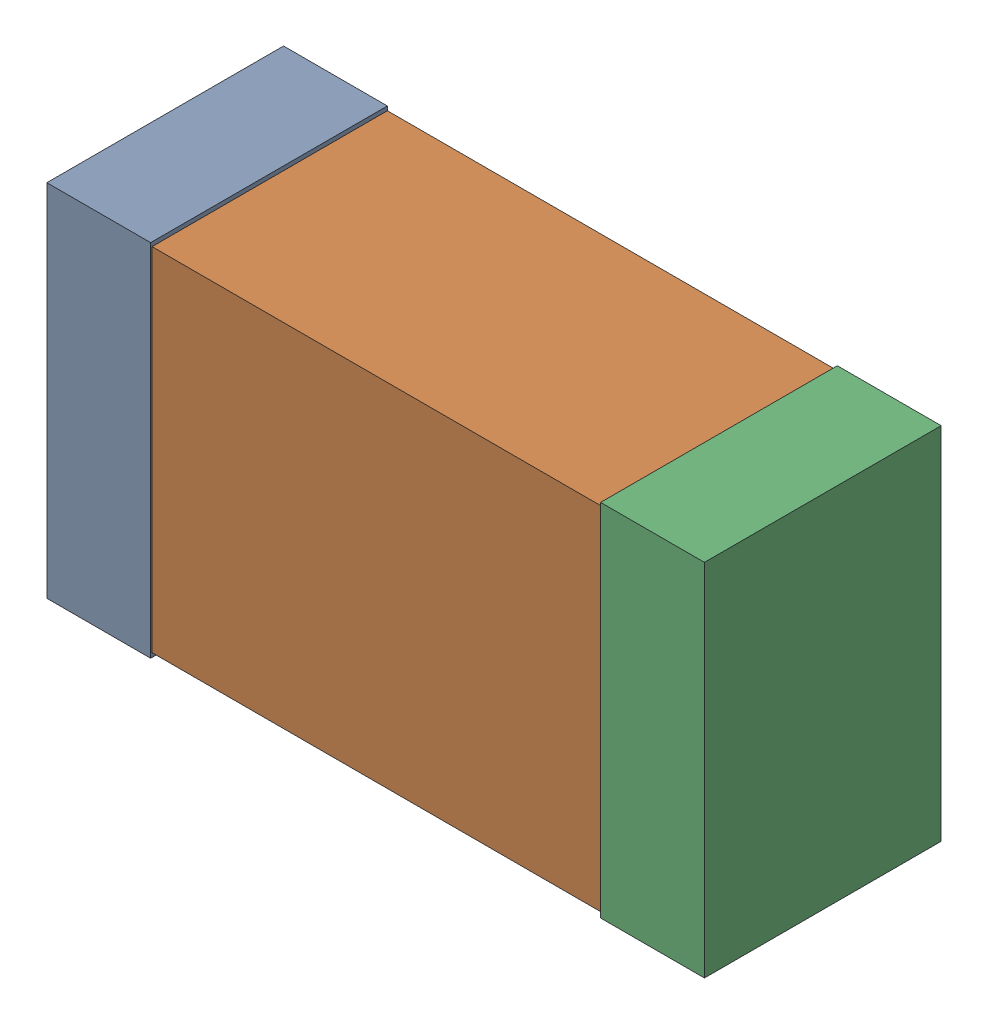
SolidWorks assembly C9_Motor_6Kanaloa_v2.0.0_Motor, configuration Default. Lengths in mm.
Overall size (2.38 1.3 0.85).
6 component instances, 2 part files, 0 mates.
Components (placement in the parent):
- 352877648-1: 352877648 [Default] at (33.798 132.588 0) size (0.38 1.3 0.85)
  - Extruded_14-1: Extruded_14 [Default] at origin size (0.38 1.3 0.85)
- 352877392-1: 352877392 [Default] at (34.798 132.588 0) size (2.2 1.27 0.85)
  - Extruded_15-1: Extruded_15 [Default] at origin size (2.2 1.27 0.85)
- 352877648-2: 352877648 [Default] at (35.798 132.588 0) size (0.38 1.3 0.85)
  - Extruded_14-1: Extruded_14 [Default] at origin size (0.38 1.3 0.85)
